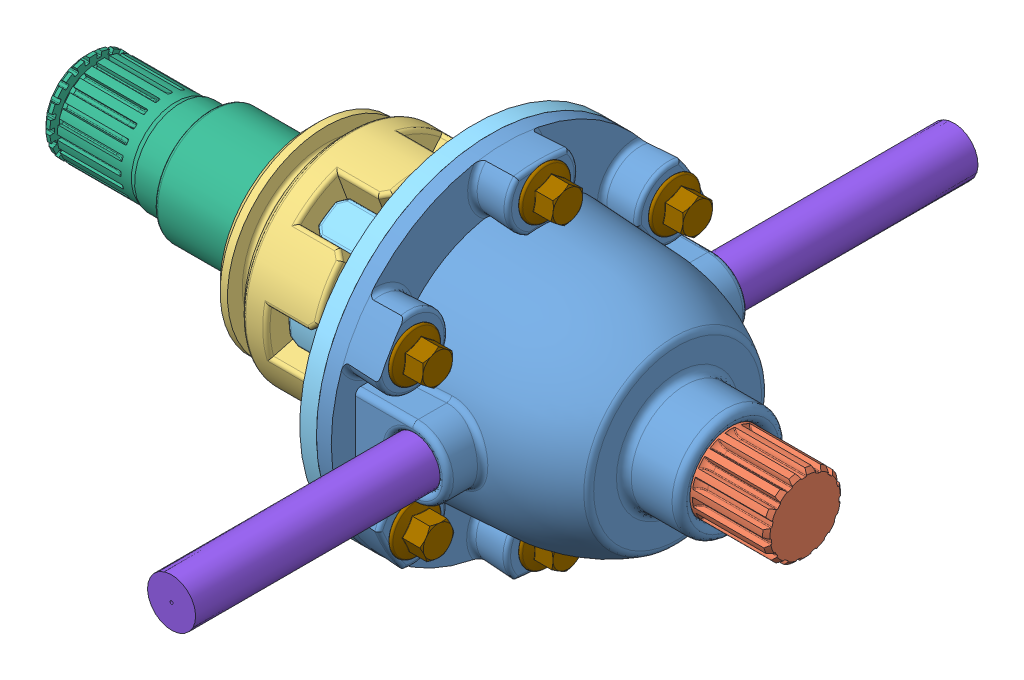
SolidWorks assembly Asssembly, configuration Default. Lengths in mm.
Overall size (194.2 128.41 211.22).
15 component instances, 9 part files, 31 mates.
Components (placement in the parent):
- Cover-1: Cover [Default] at (7.3451 49.8117 72.3476) size (65.5 94.94 94)
- Rotating_Gear_Nob-1: Rotating_Gear_Nob [Default] at (37.7889 -14.5677 59.5062) x (-1 0 0) z (0 0.961616 -0.274399) size (56.79 57.75 58.17)
- Teeths-1: Teeths [Default] at (-28.1549 49.8117 72.3476) x (0 0.927782 -0.373123) z (0 -0.373123 -0.927782) size (58 32.06 58)
- Gear_Cuts-1: Gear_Cuts [Default] at (8.4413 -8.9585 101.5996) x (1 0 0) z (0 0.999915 0.013013) size (19.79 57.75 58.17)
- Gear_1-1: Gear_1 [Default] at (6.8451 49.8117 72.3476) x (-1 0 0) z (0 -0.866025 -0.5) size (36 94 94)
- Gear_Rod-1: Gear_Rod [Default] at (10.5914 49.8117 72.3476) x (-1 0 0) z (0 -0.952451 -0.304692) size (116.5 33.5 33.5)
- washer-1: washer [Default] at (49.8451 49.8117 72.3476) x (0 0.999996 -0.002751) z (0 0.002751 0.999996) size (44 3.35 44)
- straight miter gear_iso-1: straight miter gear_iso [ISO - Straight miter gear 2.75M12T 20PA 8FW ---12O13H100MD0.8N] at (22.8451 49.8117 97.3476) x (0 0 -1) z (0.739238 -0.673445 0) size (90.62 36.5 36.5)
- straight miter gear_iso-2: straight miter gear_iso [ISO - Straight miter gear 2.75M12T 20PA 8FW ---12O13H100MD0.8N] at (22.8451 49.8117 47.3476) x (0 0 1) z (-0.054552 -0.998511 0) size (90.62 36.5 36.5)
- hex flange bolt small_iso-1: hex flange bolt small_iso [ISO 4162 - M6 x 20 x 20-S] at (24.1451 29.5649 107.3001) x (-1 0 0) z (0 -0.415827 0.909444) size (26.8 13.6 13.6)
- hex flange bolt small_iso-2: hex flange bolt small_iso [ISO 4162 - M6 x 20 x 20-S] at (24.1451 9.4017 72.288) x (-1 0 0) z (0 0 -1) size (26.8 13.6 13.6)
- hex flange bolt small_iso-3: hex flange bolt small_iso [ISO 4162 - M6 x 20 x 20-S] at (24.1451 29.5682 37.3519) x (-1 0 0) z (0 -0.924225 -0.381849) size (26.8 13.6 13.6)
- hex flange bolt small_iso-4: hex flange bolt small_iso [ISO 4162 - M6 x 20 x 20-S] at (24.1451 70.077 37.2522) x (-1 0 0) z (0 -0.924225 -0.381849) size (26.8 13.6 13.6)
- hex flange bolt small_iso-5: hex flange bolt small_iso [ISO 4162 - M6 x 20 x 20-S] at (24.1451 69.982 107.433) x (-1 0 0) z (0 -0.924225 -0.381849) size (26.8 13.6 13.6)
- hex flange bolt small_iso-6: hex flange bolt small_iso [ISO 4162 - M6 x 20 x 20-S] at (24.1451 90.3943 72.2825) x (-1 0 0) z (0 -0.924225 -0.381849) size (26.8 13.6 13.6)
Mates (geometry in assembly coordinates):
- Concentric1: concentric aligned: cylinder of Cover-1 through (7.3451 49.8117 72.3476) axis (-1 0 0) radius 14.5; cylinder of Rotating_Gear_Nob-1 through (51.2941 49.8117 72.3476) axis (-1 0 0) radius 14
- Parallel1: parallel anti-aligned: plane of Cover-1 through (49.8451 73.5617 72.3476) normal (-1 0 0); plane of Rotating_Gear_Nob-1 through (46.4951 49.8117 72.3476) normal (1 0 0)
- Parallel2: parallel anti-aligned: plane of Cover-1 through (3.3451 96.8117 72.3476) normal (-1 0 0); plane of Gear_1-1 through (3.3451 66.8117 42.9028) normal (1 0 0)
- Concentric3: concentric aligned: cylinder of Gear_Cuts-1 through (-5.0639 49.8117 72.3476) axis (1 0 0) radius 14; cylinder of Gear_1-1 through (6.8451 49.8117 72.3476) axis (1 0 0) radius 23.5
- Coincident2: coincident anti-aligned: plane of Gear_Cuts-1 through (-5.0639 49.8117 72.3476) normal (-1 0 0); plane of Gear_1-1 through (-5.0639 56.0617 61.5223) normal (1 0 0)
- Concentric4: concentric aligned: cylinder of Gear_1-1 through (6.8451 49.8117 72.3476) axis (1 0 0) radius 47; cylinder of Gear_Rod-1 through (10.5914 49.8117 72.3476) axis (1 0 0) radius 15.25
- Distance1: distance = 1 mm aligned: plane of Gear_Cuts-1 through (9.5914 49.8117 72.3476) normal (1 0 0); plane of Gear_Rod-1 through (10.5914 53.468 60.9182) normal (1 0 0)
- Concentric5: concentric aligned: cylinder of Teeths-1 through (-28.1549 49.8117 72.3476) axis (1 0 0) radius 15.25; cylinder of Gear_Rod-1 through (10.5914 49.8117 72.3476) axis (1 0 0) radius 15.25
- Coincident4: coincident anti-aligned: plane of Teeths-1 through (-15.1549 49.8117 72.3476) normal (1 0 0); plane of Gear_1-1 through (-15.1549 49.8117 72.3476) normal (-1 0 0)
- Concentric6: concentric anti-aligned: cylinder of Rotating_Gear_Nob-1 through (51.2941 49.8117 72.3476) axis (-1 0 0) radius 14; cylinder of washer-1 through (46.4951 49.8117 72.3476) axis (1 0 0) radius 14
- Coincident5: coincident anti-aligned: plane of Rotating_Gear_Nob-1 through (46.4951 49.8117 72.3476) normal (1 0 0); plane of washer-1 through (46.4951 49.8117 72.3476) normal (-1 0 0)
- Coincident6: coincident anti-aligned: plane of Cover-1 through (49.8451 73.5617 72.3476) normal (-1 0 0); plane of washer-1 through (49.8451 49.8117 72.3476) normal (1 0 0)
- Concentric8: concentric aligned: cylinder of Cover-1 through (22.8451 49.8117 119.3496) axis (0 0 -1) radius 6.5; cylinder of straight miter gear_iso-1 through (22.8451 49.8117 177.9592) axis (0 0 -1) radius 6.5
- Concentric9: concentric anti-aligned: cylinder of Cover-1 through (22.8451 49.8117 41.6976) axis (0 0 -1) radius 6.5; cylinder of straight miter gear_iso-2 through (22.8451 49.8117 -33.2639) axis (0 0 1) radius 6.5
- Coincident7: coincident anti-aligned: plane of Cover-1 through (22.8451 49.8117 47.3476) normal (0 0 1); plane of straight miter gear_iso-2 through (22.8451 49.8117 47.3476) normal (0 0 -1)
- GearMate2: gear = 26.17 : 12 mm: circle of straight miter gear_iso-2; circle of Rotating_Gear_Nob-1
- GearMate3: gear = 12 : 13 mm: circle of straight miter gear_iso-1; circle of Rotating_Gear_Nob-1
- Coincident9: coincident anti-aligned: plane of Cover-1 through (3.3451 96.8117 72.3476) normal (-1 0 0); plane of Gear_1-1 through (3.3451 66.8117 42.9028) normal (1 0 0)
- Concentric12: concentric anti-aligned: cylinder of Cover-1 through (-24.6549 29.5617 37.2736) axis (1 0 0) radius 3; cylinder of Gear_1-1 through (6.8451 29.5617 37.2736) axis (-1 0 0) radius 3
- Concentric13: concentric anti-aligned: cylinder of Cover-1 through (-24.6549 29.5617 107.4217) axis (1 0 0) radius 3; cylinder of Gear_1-1 through (6.8451 29.5617 107.4217) axis (-1 0 0) radius 3
- GearMate4: gear = 12 : 13 mm: circle of straight miter gear_iso-2; circle of Gear_Cuts-1
- Concentric18: concentric aligned: cylinder of Gear_Rod-1 through (-10.9086 53.9257 62.1459) axis (-1 0 0) radius 0.25; cylinder of Gear_Cuts-1 through (-7.6349 53.9257 62.1459) axis (-1 0 0) radius 0.25
- Coincident13: coincident aligned: plane of Cover-1 through (17.3451 49.8117 72.3476) normal (1 0 0); circle of hex flange bolt small_iso-1
- Coincident15: coincident anti-aligned: plane of Cover-1 through (17.3451 49.8117 72.3476) normal (1 0 0); plane of hex flange bolt small_iso-2 through (17.3451 14.0205 72.288) normal (-1 0 0)
- Coincident16: coincident anti-aligned: plane of Cover-1 through (17.3451 49.8117 72.3476) normal (1 0 0); plane of hex flange bolt small_iso-3 through (17.3451 31.3318 33.0831) normal (-1 0 0)
- Coincident17: coincident anti-aligned: plane of Cover-1 through (17.3451 49.8117 72.3476) normal (1 0 0); plane of hex flange bolt small_iso-4 through (17.3451 71.8407 32.9834) normal (-1 0 0)
- Coincident18: coincident anti-aligned: plane of Cover-1 through (17.3451 49.8117 72.3476) normal (1 0 0); plane of hex flange bolt small_iso-6 through (17.3451 92.158 68.0137) normal (-1 0 0)
- Coincident19: coincident anti-aligned: plane of Cover-1 through (17.3451 49.8117 72.3476) normal (1 0 0); plane of hex flange bolt small_iso-5 through (17.3451 71.7457 103.1641) normal (-1 0 0)
- GearMate5: gear = 12 : 13 mm: circle of straight miter gear_iso-1; circle of Gear_Cuts-1
- Concentric19: concentric aligned: cylinder of Cover-1 through (22.8451 49.8117 119.3496) axis (0 0 -1) radius 6.5; cylinder of straight miter gear_iso-1 through (22.8451 49.8117 177.9592) axis (0 0 -1) radius 6.5
- Coincident22: coincident aligned: circle of Cover-1; plane of straight miter gear_iso-1 through (22.8451 49.8117 97.3476) normal (0 0 1)
